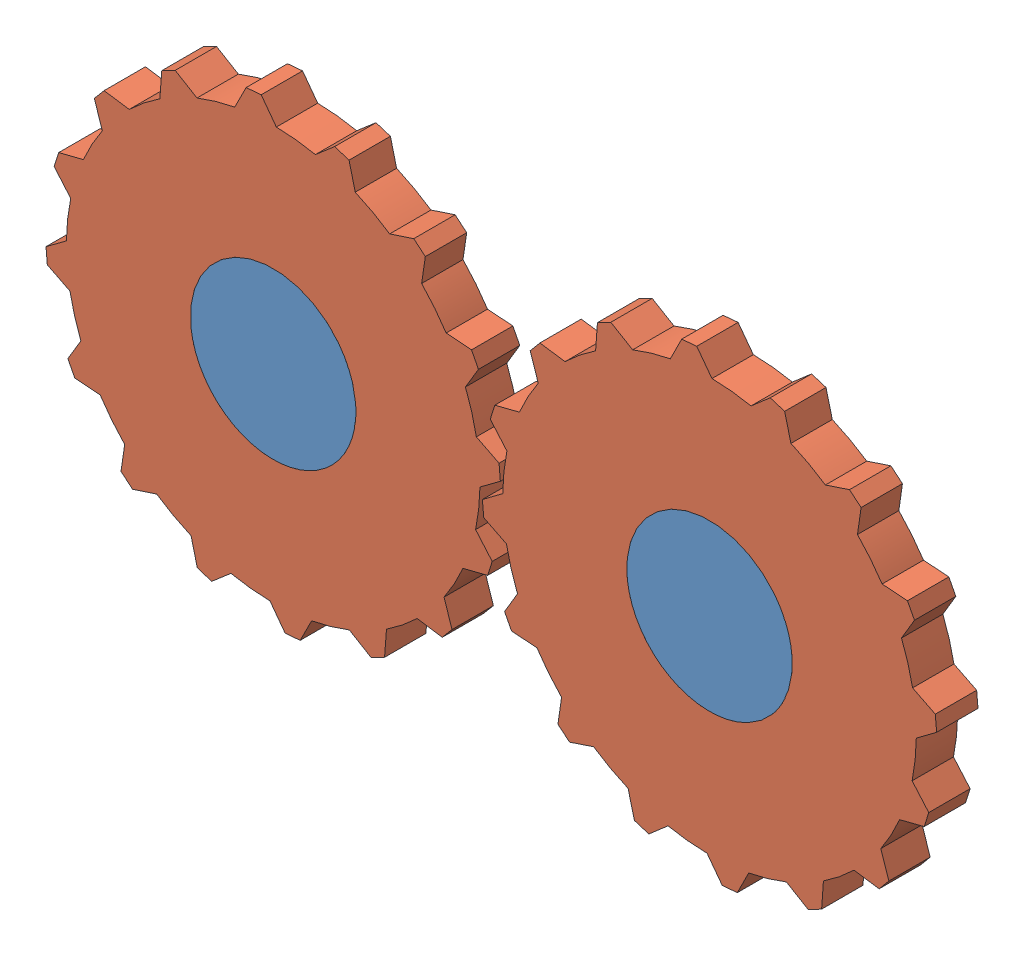
SolidWorks assembly Assem4_anim, configuration Default. Lengths in mm.
Overall size (233.86 137.76 10).
3 component instances, 2 part files, 4 mates.
Components (placement in the parent):
- plane_3d_3-1: plane_3d_3 [Default] at (41.2696 82.5704 114.0541) size (145.5 40 10)
- gear_3d_2-1: gear_3d_2 [Default] at (-10.0994 77.5395 114.0541) x (0.085748 -0.996317 0) z (0 0 1) size (109.94 109.94 10)
- gear_3d_2-2: gear_3d_2 [Default] at (95.4006 77.5395 114.0541) x (0.298707 0.954345 0) z (0 0 1) size (109.94 109.94 10)
Mates (geometry in assembly coordinates):
- Coincident1: coincident aligned: plane of plane_3d_3-1 through (41.2696 82.5704 124.0541) normal (0 0 1); plane of gear_3d_2-1 through (-10.0994 77.5395 124.0541) normal (0 0 1)
- Coincident2: coincident aligned: plane of plane_3d_3-1 through (41.2696 82.5704 124.0541) normal (0 0 1); plane of gear_3d_2-2 through (95.4006 77.5395 124.0541) normal (0 0 1)
- Coincident3: coincident aligned: circle of plane_3d_3-1; circle of gear_3d_2-1
- Coincident4: coincident aligned: circle of plane_3d_3-1; circle of gear_3d_2-2
